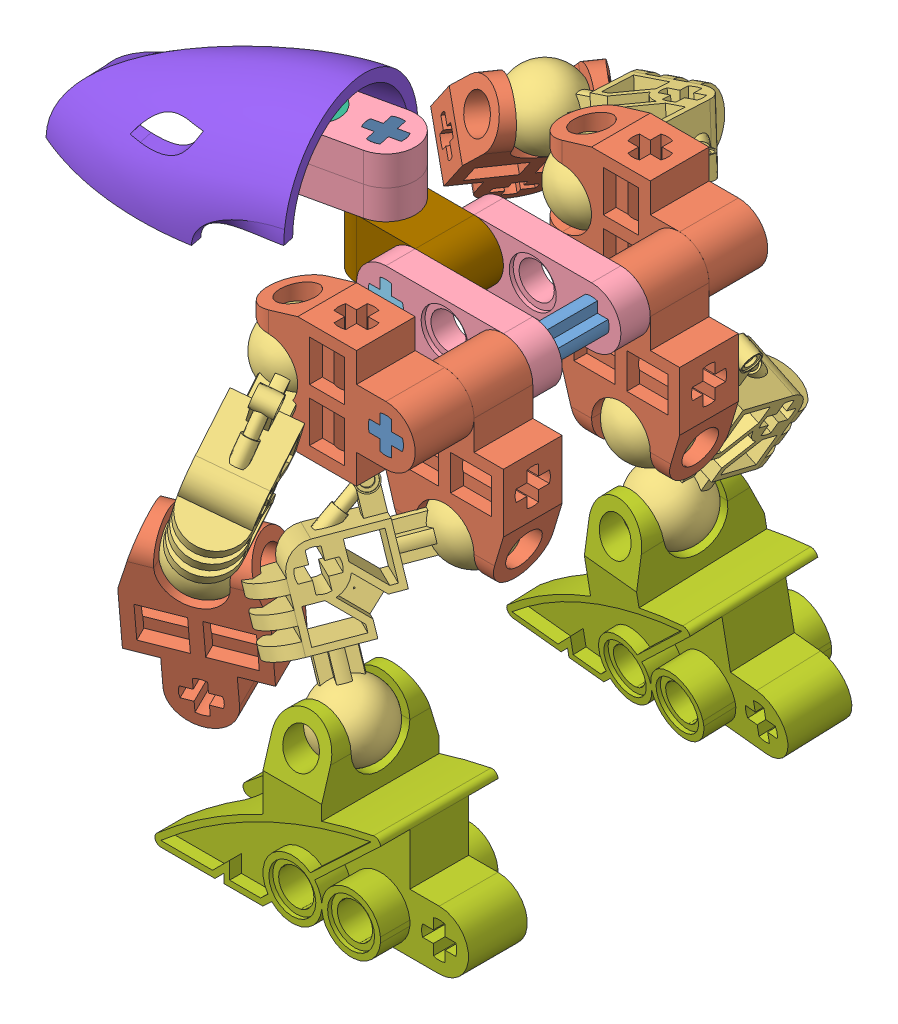
SolidWorks assembly colorful fire guy, configuration Default. Lengths in mm.
Overall size (50.18 45 56.51).
22 component instances, 10 part files, 45 mates.
Components (placement in the parent):
- cross axle 6-1: cross axle 6 [Default] at (5.6374 15.0402 11.3801) x (1 0 0) z (0 -1 0) size (3 30 3)
- the hand-1: the hand [Default] at (5.6374 7.5402 21.3801) x (-1 0 0) z (0 -1 0) size (10 5 15)
- the hand-2: the hand [Default] at (5.6374 7.5402 36.3801) x (-1 0 0) z (0 -1 0) size (10 5 15)
- the hand-3: the hand [Default] at (-5.4614 -0.6016 46.5805) x (0.926139 -0.006842 -0.37712) z (0.066924 0.986952 0.146447) size (10 5 15)
- the hand-4: the hand [Default] at (-1.8626 15.0402 16.3801) x (0 1 0) z (-1 0 0) size (10 5 15)
- the hand-5: the hand [Default] at (-15.6676 7.5731 6.7655) x (0.491885 -0.064561 -0.868263) z (0.601189 0.746528 0.285074) size (10 5 15)
- the hand-6: the hand [Default] at (-1.8626 15.0402 41.3801) x (0 1 0) z (-1 0 0) size (10 5 15)
- link 2x2-1: link 2x2 [Default] at (0.2286 3.38 42.1256) x (0.540879 0.166023 -0.824552) z (0.416774 -0.904415 0.091287) size (17.5 6 18.1)
- link 2x2-2: link 2x2 [Default] at (-6.1427 12.8703 4.282) x (0.178005 0.216993 0.959806) z (-0.95964 -0.177533 0.218111) size (17.5 6 18.1)
- link 2x2-3: link 2x2 [Default] at (4.7533 2.0386 9.3822) x (0.088407 0.30016 0.949783) z (-0.380525 -0.871019 0.310688) size (17.5 6 18.1)
- link 2x2-4: link 2x2 [Default] at (-1.6457 10.7033 47.4713) x (-0.271686 0.43369 -0.859127) z (-0.457637 -0.843536 -0.281099) size (17.5 6 18.1)
- technic lever 3-2: technic lever 3 [Default] at (-14.2454 17.5402 27.4562) x (-0.976563 0 0.215232) z (-0.215232 0 -0.976563) size (15 2.5 5)
- technic lever 3-3: technic lever 3 [Default] at (0.6374 15.0402 23.8801) x (1 0 0) z (0 1 0) size (15 2.5 5)
- technic lever 3-4: technic lever 3 [Default] at (0.6374 15.0402 28.8801) x (1 0 0) z (0 -1 0) size (15 2.5 5)
- technic lever 3-5: technic lever 3 [Default] at (-14.2454 22.5402 27.4562) x (-0.976563 0 0.215232) z (0.215232 0 0.976563) size (15 2.5 5)
- cross axle 2-1: cross axle 2 [Default] at (-4.3626 15.0402 21.3801) x (1 0 0) z (0 -1 0) size (3 10 3)
- connector peg w knob-1: connector peg w knob [Default] at (-14.2454 17.5402 27.4562) size (4 6 4)
- the foot-1: the foot [Default] at (-1.2397 -19.0748 10.5199) x (0.994379 0.009425 0.105463) z (-0.103044 -0.142965 0.984349) size (25 15 10)
- the foot-2: the foot [Default] at (1.8963 -18.1642 43.0987) size (25 15 10)
- fire mask-1: fire mask [Default] at (-11.804 15.0402 26.9181) x (-0.976563 0 0.215232) z (-0.215232 0 -0.976563) size (20.36 10.1 15.04)
- cross block 90-1: cross block 90 [Default] at (-6.8626 17.5402 26.3801) x (-1 0 0) z (0 0 1) size (10 5 5)
- connector peg-cross axle-1: connector peg-cross axle [Default] at (-9.3626 12.5402 26.3801) x (-0.976563 0 0.215232) z (-0.215232 0 -0.976563) size (4 10 4)
Mates (geometry in assembly coordinates):
- Concentric1: concentric anti-aligned: circle of cross axle 6-1; circle of the hand-6
- Coincident2: coincident aligned: plane of cross axle 6-1 through (5.6374 15.0402 41.3801) normal (0 0 1); plane of the hand-6 through (-1.8626 15.0402 41.3801) normal (0 0 1)
- Coincident3: coincident anti-aligned: plane of cross axle 6-1 through (6.1374 13.5402 41.3801) normal (1 0 0); plane of the hand-6 through (6.1374 15.0402 36.3801) normal (-1 0 0)
- Concentric2: concentric anti-aligned: cylinder of cross axle 6-1 through (5.6374 15.0402 11.3791) axis (0 0 1) radius 1.5; circle of the hand-2
- Coincident4: coincident anti-aligned: plane of the hand-2 through (5.6374 7.5402 36.3801) normal (0 0 1); plane of the hand-6 through (-1.8626 15.0402 36.3801) normal (0 0 -1)
- Parallel1: parallel aligned: plane of the hand-2 through (5.6374 12.5402 31.3801) normal (0 1 0); plane of the hand-6 through (-1.8626 20.0402 36.3801) normal (0 1 0)
- Concentric3: concentric anti-aligned: circle of the hand-1; cylinder of the hand-2 through (5.6374 15.0402 31.3801) axis (0 0 1) radius 2.5
- Parallel2: parallel aligned: plane of the hand-1 through (5.6374 12.5402 16.3801) normal (0 1 0); plane of the hand-2 through (5.6374 12.5402 31.3801) normal (0 1 0)
- Coincident9: coincident aligned: plane of cross axle 6-1 through (5.6374 15.0402 11.3801) normal (0 0 -1); plane of the hand-4 through (-1.8626 15.0402 11.3801) normal (0 0 -1)
- Concentric4: concentric aligned: circle of the hand-1; circle of the hand-4
- Parallel3: parallel aligned: plane of the hand-1 through (5.6374 12.5402 16.3801) normal (0 1 0); plane of the hand-4 through (-1.8626 17.5402 11.3801) normal (0 1 0)
- Coincident12: coincident anti-aligned: plane of the hand-1 through (5.6374 7.5402 16.3801) normal (0 0 -1); plane of the hand-4 through (-1.8626 15.0402 16.3801) normal (0 0 1)
- Concentric5: concentric: sphere of the hand-2; sphere of link 2x2-1
- Concentric6: concentric: sphere of the hand-1; sphere of link 2x2-3
- Concentric7: concentric: sphere of the hand-4; sphere of link 2x2-2
- Concentric8: concentric: sphere of the hand-6; sphere of link 2x2-4
- Coincident13: coincident anti-aligned: plane of the hand-1 through (5.6374 7.5402 21.3801) normal (0 0 1); plane of technic lever 3-3 through (0.6374 15.0402 21.3801) normal (0 0 -1)
- Concentric9: concentric aligned: cylinder of the hand-1 through (5.6374 15.0402 16.3801) axis (0 0 1) radius 2.5; cylinder of technic lever 3-3 through (5.6374 15.0402 22.6301) axis (0 0 1) radius 2.5
- Parallel4: parallel aligned: plane of the hand-4 through (-1.8626 20.0402 11.3801) normal (0 1 0); plane of technic lever 3-3 through (0.6374 17.5402 22.6301) normal (0 1 0)
- Coincident15: coincident anti-aligned: plane of the hand-2 through (5.6374 7.5402 31.3801) normal (0 0 -1); plane of technic lever 3-4 through (0.6374 15.0402 31.3801) normal (0 0 1)
- Parallel5: parallel aligned: plane of the hand-2 through (5.6374 12.5402 31.3801) normal (0 1 0); plane of technic lever 3-4 through (0.6374 17.5402 30.1301) normal (0 1 0)
- Concentric10: concentric anti-aligned: cylinder of the hand-2 through (5.6374 15.0402 31.3801) axis (0 0 1) radius 2.5; cylinder of technic lever 3-4 through (5.6374 15.0402 30.1301) axis (0 0 -1) radius 2.5
- Coincident17: coincident aligned: plane of technic lever 3-4 through (0.6374 15.0402 31.3801) normal (0 0 1); plane of cross axle 2-1 through (-4.3626 15.0402 31.3801) normal (0 0 1)
- Parallel6: parallel aligned: plane of technic lever 3-3 through (0.6374 17.5402 22.6301) normal (0 1 0); plane of cross axle 2-1 through (-5.8626 15.5402 31.3801) normal (0 1 0)
- Concentric11: concentric anti-aligned: cylinder of technic lever 3-4 through (-4.3626 15.0402 30.1301) axis (0 0 -1) radius 2.5; cylinder of cross axle 2-1 through (-4.3626 15.0402 21.3791) axis (0 0 1) radius 1.5
- Concentric12: concentric aligned: cylinder of technic lever 3-3 through (-4.3626 15.0402 22.6301) axis (0 0 1) radius 2.5; cylinder of cross block 90-1 through (-4.3626 15.0402 23.8791) axis (0 0 1) radius 2.5
- Parallel7: parallel aligned: plane of technic lever 3-4 through (0.6374 17.5402 30.1301) normal (0 1 0); plane of cross block 90-1 through (-6.8626 17.5402 26.3801) normal (0 1 0)
- Coincident20: coincident anti-aligned: plane of technic lever 3-3 through (0.6374 15.0402 23.8801) normal (0 0 1); plane of cross block 90-1 through (-6.8626 12.5402 23.8801) normal (0 0 -1)
- Concentric13: concentric anti-aligned: cylinder of cross block 90-1 through (-9.3626 12.5402 26.3801) axis (0 1 0) radius 1.5; cylinder of connector peg-cross axle-1 through (-9.3626 17.5402 26.3801) axis (0 -1 0) radius 1.5
- Coincident21: coincident aligned: plane of cross block 90-1 through (-6.8626 12.5402 26.3801) normal (0 -1 0); plane of connector peg-cross axle-1 through (-9.3626 12.5402 26.3801) normal (0 -1 0)
- Concentric14: concentric aligned: cylinder of technic lever 3-2 through (-9.3626 18.7902 26.3801) axis (0 -1 0) radius 2.5; cylinder of connector peg-cross axle-1 through (-9.3626 22.5402 26.3801) axis (0 -1 0) radius 1.5
- Coincident22: coincident anti-aligned: plane of technic lever 3-2 through (-14.2454 17.5402 27.4562) normal (0 -1 0); plane of cross block 90-1 through (-6.8626 17.5402 26.3801) normal (0 1 0)
- Parallel8: parallel aligned: plane of technic lever 3-2 through (-14.7835 18.7902 25.0148) normal (-0.215232 0 -0.976563); plane of connector peg-cross axle-1 through (-9.4702 22.5402 25.8918) normal (-0.215232 0 -0.976563)
- Coincident24: coincident anti-aligned: plane of technic lever 3-2 through (-14.2454 20.0402 27.4562) normal (0 1 0); plane of technic lever 3-5 through (-14.2454 20.0402 27.4562) normal (0 -1 0)
- Coincident26: coincident anti-aligned: circle of technic lever 3-5; circle of connector peg-cross axle-1
- Concentric15: concentric aligned: cylinder of technic lever 3-2 through (-14.2454 18.7902 27.4562) axis (0 -1 0) radius 1.5; cylinder of connector peg w knob-1 through (-14.2454 22.5402 27.4562) axis (0 -1 0) radius 1.5
- Coincident27: coincident aligned: plane of technic lever 3-2 through (-14.2454 17.5402 27.4562) normal (0 -1 0); plane of connector peg w knob-1 through (-14.2454 17.5402 27.4562) normal (0 -1 0)
- Concentric16: concentric anti-aligned: cylinder of technic lever 3-5 through (-14.2454 21.2902 27.4562) axis (0 1 0) radius 1.5; cylinder of connector peg w knob-1 through (-14.2454 22.5402 27.4562) axis (0 -1 0) radius 1.5
- Concentric17: concentric aligned: cylinder of technic lever 3-5 through (-19.1282 21.2902 28.5324) axis (0 1 0) radius 1.5; cylinder of fire mask-1 through (-19.1282 25.12 28.5324) axis (0 1 0) radius 1.5
- Coincident28: coincident: circle of technic lever 3-2; plane of fire mask-1 through (-11.804 20.0402 26.9181) normal (0 -1 0)
- Parallel10: parallel anti-aligned: plane of technic lever 3-2 through (-18.64 18.7902 28.4248) normal (-0.976563 0 0.215232); plane of fire mask-1 through (-18.64 25.12 28.4248) normal (0.976563 0 -0.215232)
- Concentric18: concentric: sphere of link 2x2-3; sphere of the foot-1
- Concentric19: concentric: sphere of link 2x2-1; sphere of the foot-2
- Concentric20: concentric: sphere of the hand-3; sphere of link 2x2-4
- Concentric21: concentric: sphere of the hand-5; sphere of link 2x2-2
